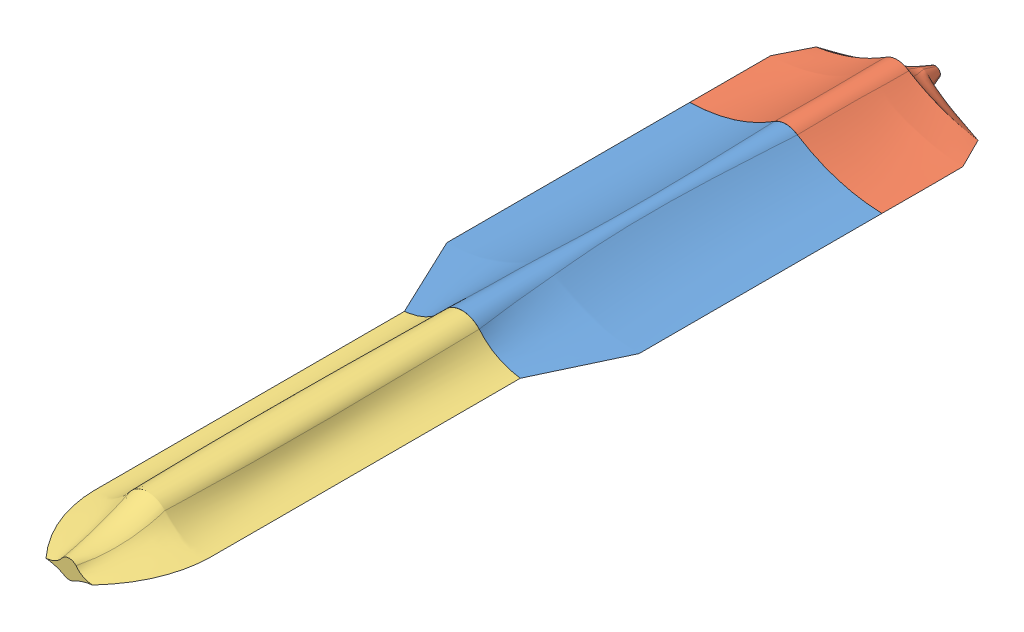
SolidWorks assembly Assem1, configuration Default. Lengths in mm.
Overall size (6918.88 1661.48 30245.24).
3 component instances, 3 part files, 5 mates.
Components (placement in the parent):
- SR-71_Rear_Fuselage_Front (1)-1: SR-71_Rear_Fuselage_Front (1) [Default] at (-31.2414 -226.6805 5703.9933) size (6918.88 1656.03 11441.93)
- SR-71_Rear_Fuselage_Rear (2)-1: SR-71_Rear_Fuselage_Rear (2) [Default] at (-31.6402 -226.2012 -2769.4467) size (6917.62 1642.41 5323.18)
- SR-71_Fuselage (2)-1: SR-71_Fuselage (2) [Default] at (-31.2414 -226.6805 19419.9933) size (4049.7 1660.19 13778.05)
Mates (geometry in assembly coordinates):
- Coincident4: coincident aligned: circle of SR-71_Rear_Fuselage_Front (1)-1; circle of SR-71_Rear_Fuselage_Rear (2)-1
- Coincident5: coincident anti-aligned: plane of SR-71_Rear_Fuselage_Front (1)-1 through (-1169.4466 -378.4636 5703.9933) normal (0 0 1); plane of SR-71_Fuselage (2)-1 through (-1169.4466 -378.4636 5703.9933) normal (0 0 -1)
- Concentric2: concentric anti-aligned: circle of SR-71_Rear_Fuselage_Front (1)-1; circle of SR-71_Fuselage (2)-1
- Lock1: lock: unknown of SR-71_Rear_Fuselage_Front (1)-1; unknown of SR-71_Fuselage (2)-1
- Lock2: lock: unknown of SR-71_Rear_Fuselage_Front (1)-1; unknown of SR-71_Rear_Fuselage_Rear (2)-1
